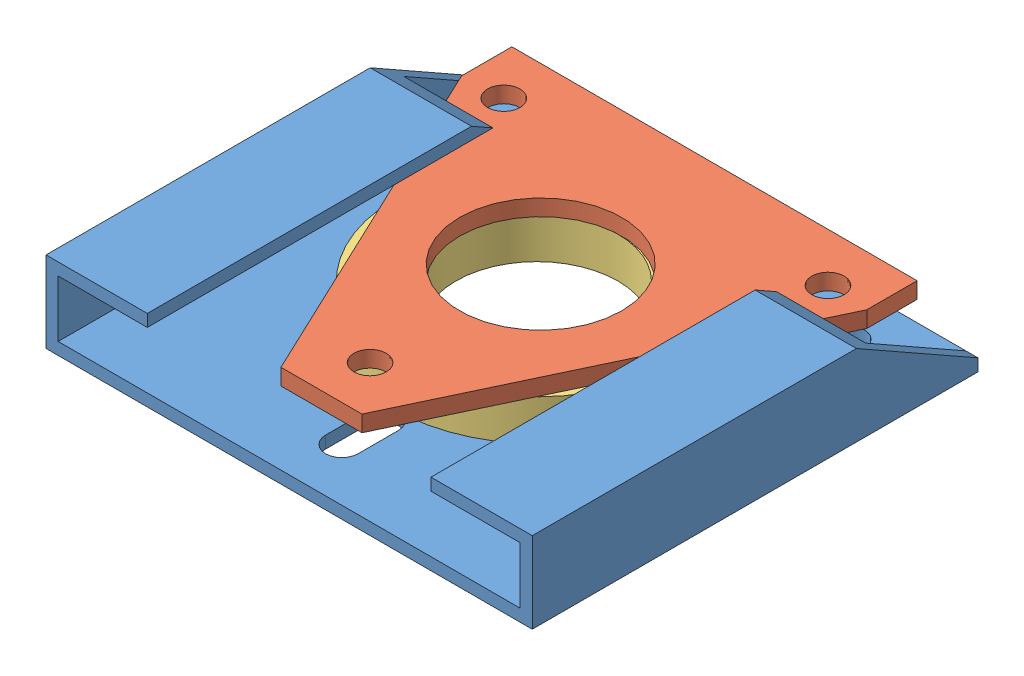
SolidWorks assembly Assem 3, configuration Default. Lengths in mm.
Overall size (120 20 110).
3 component instances, 3 part files, 5 mates.
Components (placement in the parent):
- rear axle carrier-1: rear axle carrier [Default] at (107.7245 196.5575 405.2583) size (120 20 110)
- triangle-1: triangle [Default] at (129.1495 209.5575 372.9696) x (1 0 0) z (0 1 0) size (100 97 4)
- bearings-1: bearings [Default] at (106.8681 199.5575 398.2677) x (1 0 0) z (0 1 0) size (70 70 10)
Mates (geometry in assembly coordinates):
- Parallel1: parallel anti-aligned: plane of rear axle carrier-1 through (107.7245 199.5575 405.2583) normal (0 1 0); plane of triangle-1 through (129.1495 209.5575 372.9696) normal (0 -1 0)
- Coincident19: coincident anti-aligned: plane of rear axle carrier-1 through (107.7245 199.5575 405.2583) normal (0 1 0); plane of bearings-1 through (106.8681 199.5575 398.2677) normal (0 -1 0)
- Tangent1: tangent anti-aligned: cylinder of rear axle carrier-1 through (107.7245 177.5575 437.2583) axis (0 1 0) radius 4; cylinder of bearings-1 through (106.8681 209.5575 398.2677) axis (0 -1 0) radius 35
- Coincident20: coincident anti-aligned: plane of triangle-1 through (129.1495 209.5575 372.9696) normal (0 -1 0); plane of bearings-1 through (106.8681 209.5575 398.2677) normal (0 1 0)
- Coincident21: coincident aligned: circle of triangle-1; circle of assembly
